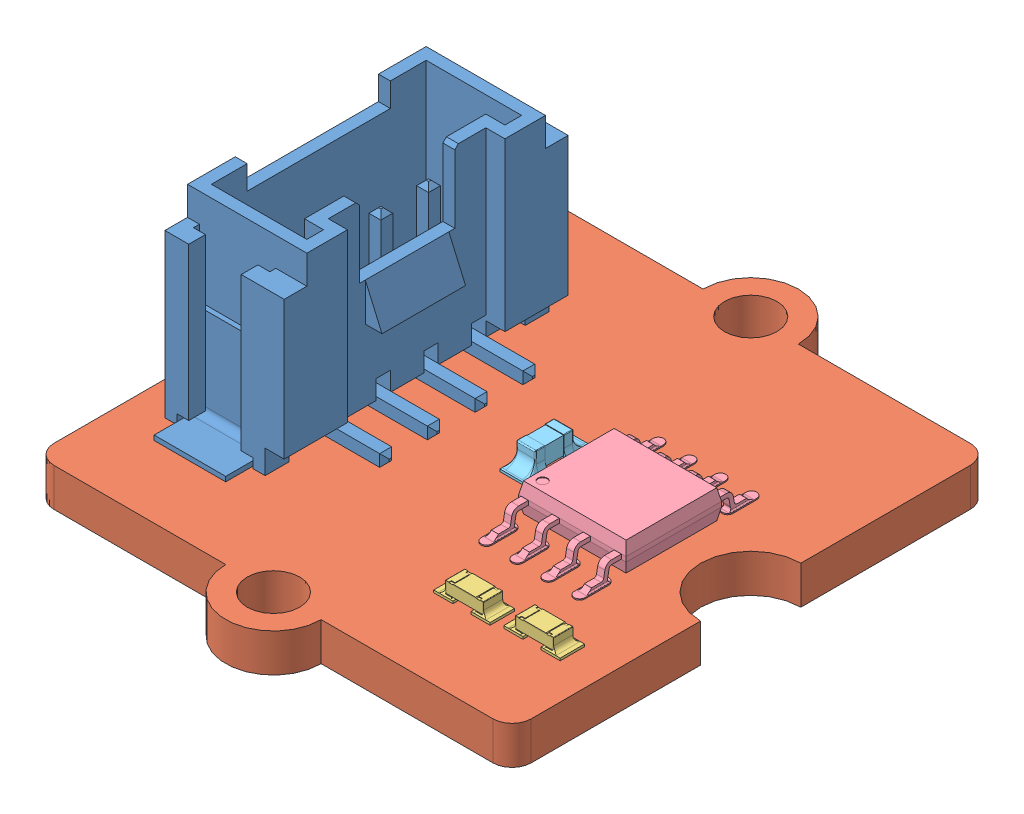
SolidWorks assembly Grove Temperature v1.2, configuration Défaut. Lengths in mm.
Overall size (20 9.6 24).
7 component instances, 5 part files, 5 mates.
Components (placement in the parent):
- PCB Grove 20x20 SMD Vertical - Temperature v1.2-1: PCB Grove 20x20 SMD Vertical - Temperature v1.2 [Défaut] at (-2.4132 -6.1012 0.0201) size (20 9.6 24)
  - Connector Grove SMD Vertical-1: Connector Grove SMD Vertical [Défaut] at (-4.1217 4.697 23.9799) x (0 0 -1) z (1 0 0) size (14 8 6.5)
  - PCB Grove 20x20 - Temprature v1.2-1: PCB Grove 20x20 - Temprature v1.2 [Défaut] at (-0.5217 3.897 23.9799) size (20 1.6 24)
- Resistor-1: Resistor [Default] at (1.6279 -1.4042 30.1549) size (2.36 0.6 1.03)
- LM 358-1: LM 358 [Default] at (1.7151 -1.4042 24.1222) x (0 0 1) z (-1 0 0) size (7.65 1.3 4.5)
- Capacitor 603-1: Capacitor 603 [Default] at (-2.0549 -1.4042 23.5033) x (0 0 1) z (-1 0 0) size (2.76 0.9 1.12)
- Resistor-2: Resistor [Default] at (4.6893 -1.1017 30.2803) size (2.36 0.6 1.03)
Mates (geometry in assembly coordinates):
- Coïncidente1: coincident anti-aligned: plane of PCB Grove 20x20 SMD Vertical - Grove Temperature v1.2-1/PCB Grove 20x20 - Grove Temprature v1.2-1 through (-2.9349 -1.4042 24) normal (0 1 0); plane of Resistor-1 through (1.6279 -1.4042 30.1549) normal (0 -1 0)
- Distance3: distance = 3.1 mm aligned: plane of LM 358-1 through (3.9651 -1.4042 24.1222) normal (1 0 0); plane of PCB Grove 20x20 SMD Vertical - Grove Temperature v1.2-1/PCB Grove 20x20 - Grove Temprature v1.2-1 through (7.0651 -1.4042 24) normal (1 0 0)
- Coïncidente5: coincident anti-aligned: plane of PCB Grove 20x20 SMD Vertical - Grove Temperature v1.2-1/PCB Grove 20x20 - Grove Temprature v1.2-1 through (-2.9349 -1.4042 24) normal (0 1 0); plane of LM 358-1 through (3.6151 -1.4042 21.5222) normal (0 -1 0)
- Coïncidente6: coincident anti-aligned: plane of PCB Grove 20x20 SMD Vertical - Grove Temperature v1.2-1/PCB Grove 20x20 - Grove Temprature v1.2-1 through (-2.9349 -1.4042 24) normal (0 1 0); plane of Capacitor 603-1 through (-2.0549 -1.4042 23.5033) normal (0 -1 0)
- Distance4: distance = 10.5 mm aligned: plane of Capacitor 603-1 through (-2.4349 -1.2792 23.9033) normal (-1 0 0); plane of PCB Grove 20x20 SMD Vertical - Grove Temperature v1.2-1/PCB Grove 20x20 - Grove Temprature v1.2-1 through (-12.9349 -1.4042 24) normal (-1 0 0)
